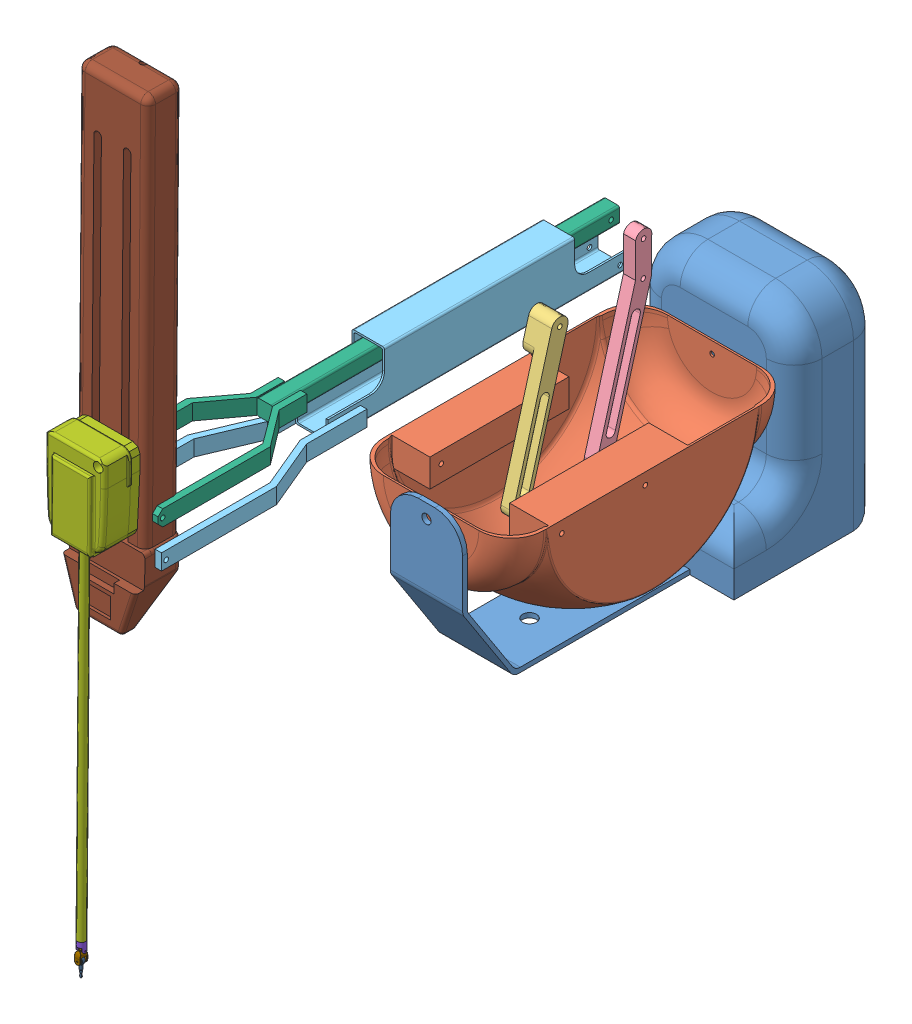
SolidWorks assembly ActiveSection_right, configuration Default. Lengths in mm.
Overall size (173.42 821.79 791.73).
11 component instances, 11 part files, 27 mates.
Components (placement in the parent):
- L1-1: L1 [Default] at (-68.7537 -23.5534 169.1519) size (173 228 404)
- L2-1: L2 [Default] at (-29.7537 67.7343 50.5284) size (173.42 143 305)
- LP12-1: LP12 [Default] at (-0.2537 151.1135 121.8589) x (0 -0.267998 -0.963419) z (1 0 0) size (18 173.91 25)
- LP11-1: LP11 [Default] at (-0.2537 95.7196 44.9923) x (0 -0.269759 -0.962928) z (1 0 0) size (27.97 209.62 13)
- LP21-1: LP21 [Default] at (-27.3141 259.523 7.7454) size (96 58 534)
- LP22-1: LP22 [Default] at (0.8884 224.0342 7.4385) size (90 17 534)
- L4-1: L4 [Default] at (-29.7537 215.3788 576.9644) x (1 0 0) z (0 -0.999966 0.008294) size (68.49 43.05 464)
- L5-1: L5 [Default] at (-29.7537 -151.4086 580.0064) x (1 0 0) z (0 -0.999966 0.008294) size (8.32 8.32 11)
- L6-1: L6 [Default] at (-66.6018 -121.6279 583.9596) x (0 -0.999966 0.008294) z (0 -0.008294 -0.999966) size (14.9 6.29 8.98)
- L7-1: L7 [Default] at (-30.0037 -174.0474 580.2442) x (1 0 0) z (0 -0.999966 0.008294) size (6 3.3 19.83)
- L3_right-1: L3_right [Default] at (-26.1906 634.2205 507.9112) x (1 0 0) z (0 -0.999966 0.008294) size (82 50 500)
Mates (geometry in assembly coordinates):
- Coincident1: coincident anti-aligned: plane of L1-1 through (9.2463 70.2343 203.0301) normal (0 0 -1); plane of L2-1 through (-29.7537 67.7343 203.0301) normal (0 0 1)
- Concentric1: concentric aligned: cylinder of L1-1 through (-29.7537 55.2343 -195.9699) axis (0 0 1) radius 5; circle of L2-1
- Coincident2: coincident anti-aligned: plane of L2-1 through (12.7463 37.7343 160.8722) normal (-1 0 0); plane of LP12-1 through (12.7463 205.4449 106.7454) normal (1 0 0)
- Concentric2: concentric anti-aligned: cylinder of L2-1 through (-116.4646 55.2343 148.5301) axis (1 0 0) radius 2.5; cylinder of LP12-1 through (12.7463 55.2343 148.5301) axis (-1 0 0) radius 2.5
- Coincident3: coincident anti-aligned: plane of LP12-1 through (-12.2537 205.4449 106.7454) normal (-1 0 0); plane of LP21-1 through (-12.2537 253.4449 331.7454) normal (1 0 0)
- Concentric3: concentric anti-aligned: cylinder of LP12-1 through (12.7463 205.4449 106.7454) axis (-1 0 0) radius 2.5; cylinder of LP21-1 through (-47.2537 205.4449 106.7454) axis (1 0 0) radius 2.5
- Coincident4: coincident anti-aligned: plane of L2-1 through (12.7463 37.7343 160.8722) normal (-1 0 0); plane of LP11-1 through (12.7463 242.4436 16.4385) normal (1 0 0)
- Concentric4: concentric anti-aligned: cylinder of L2-1 through (-116.4646 55.2343 58.5301) axis (1 0 0) radius 2.5; cylinder of LP11-1 through (12.7463 55.2343 58.5301) axis (-1 0 0) radius 2.5
- Concentric5: concentric anti-aligned: cylinder of LP11-1 through (12.7463 205.4449 16.7454) axis (-1 0 0) radius 2.5; cylinder of LP21-1 through (-47.2537 205.4449 16.7454) axis (1 0 0) radius 2.5
- Concentric6: concentric anti-aligned: cylinder of LP11-1 through (12.7463 242.4436 16.4385) axis (-1 0 0) radius 2.5; cylinder of LP22-1 through (-75.7537 242.4436 16.4385) axis (1 0 0) radius 2.5
- Distance1: distance = 8 mm anti-aligned: plane of LP22-1 through (-22.2537 248.9436 381.4385) normal (1 0 0); plane of LP21-1 through (-14.2537 251.4449 331.7454) normal (-1 0 0)
- Coincident11: coincident anti-aligned: plane of L4-1 through (-29.7537 -102.8233 579.6035) normal (0 -0.999966 0.008294); plane of L5-1 through (-29.7537 -102.8233 579.6035) normal (0 0.999966 -0.008294)
- Concentric12: concentric aligned: cylinder of L4-1 through (-29.7537 -102.8233 579.6035) axis (0 0.999966 -0.008294) radius 4.2; cylinder of L5-1 through (-29.7537 -113.8229 579.6947) axis (0 0.999966 -0.008294) radius 4.16
- Concentric13: concentric anti-aligned: cylinder of L5-1 through (-33.9137 -111.923 579.679) axis (1 0 0) radius 0.7; cylinder of L6-1 through (-26.9037 -111.923 579.679) axis (-1 0 0) radius 0.65
- Distance2: distance = 2 mm anti-aligned: plane of L6-1 through (-28.5537 -158.7208 578.567) normal (1 0 0); plane of L5-1 through (-26.5537 -163.3001 575.9449) normal (-1 0 0)
- Distance3: distance = 1 mm anti-aligned: plane of L7-1 through (-28.6537 -166.0614 578.5279) normal (0 -0.008294 -0.999966); plane of L6-1 through (-26.9037 -186.329 577.696) normal (0 0.008294 0.999966)
- Concentric14: concentric anti-aligned: cylinder of L6-1 through (-30.0037 -121.6861 584.1594) axis (0 -0.008294 -0.999966) radius 0.65; cylinder of L7-1 through (-30.0037 -121.7359 578.1603) axis (0 0.008294 0.999966) radius 0.65
- Parallel1: parallel aligned: plane of L1-1 through (6.7463 78.2343 -195.9699) normal (0 0 -1); plane of LP11-1 through (12.7463 206.1387 7.7721) normal (0 0 -1)
- Parallel2: parallel aligned: plane of L4-1 through (4.3473 344.6538 587.0425) normal (0 0.008294 0.999966); plane of L6-1 through (-30.1037 -121.9878 583.9626) normal (0 0.008294 0.999966)
- Parallel3: parallel aligned: plane of L6-1 through (-30.1037 -121.9878 583.9626) normal (0 0.008294 0.999966); plane of L7-1 through (-31.0837 -138.5591 580.2499) normal (0 0.008294 0.999966)
- Parallel4: parallel aligned: plane of L1-1 through (6.7463 128.2343 -195.9699) normal (0 1 0); plane of L2-1 through (-172.7537 67.7343 -92.4716) normal (0 1 0)
- Concentric15: concentric aligned: cylinder of LP22-1 through (-75.7537 242.4436 536.4385) axis (1 0 0) radius 2.5; cylinder of L3_right-1 through (-70.7537 242.4436 536.4385) axis (1 0 0) radius 2.5
- Concentric16: concentric aligned: cylinder of LP21-1 through (-77.7537 205.4449 536.7454) axis (1 0 0) radius 2.5; cylinder of L3_right-1 through (-70.7537 205.4449 536.7454) axis (1 0 0) radius 2.5
- Coincident13: coincident anti-aligned: plane of LP21-1 through (-70.7537 214.4449 541.7454) normal (1 0 0); plane of L3_right-1 through (-70.7537 134.24 512.3351) normal (-1 0 0)
- Coincident16: coincident anti-aligned: plane of L4-1 through (-61.8537 222.606 549.6035) normal (0 -0.008294 -0.999966); plane of L3_right-1 through (-67.7537 214.5524 549.6703) normal (0 0.008294 0.999966)
- Coincident17: coincident anti-aligned: plane of L4-1 through (-41.6537 282.4583 562.1575) normal (1 0 0); plane of L3_right-1 through (-41.6537 574.2912 516.6856) normal (-1 0 0)
- Distance4: distance = 5 mm anti-aligned: plane of L4-1 through (4.3463 219.6356 559.6785) normal (0 -0.999966 0.008294); plane of L3_right-1 through (11.2463 214.6519 561.6699) normal (0 0.999966 -0.008294)
